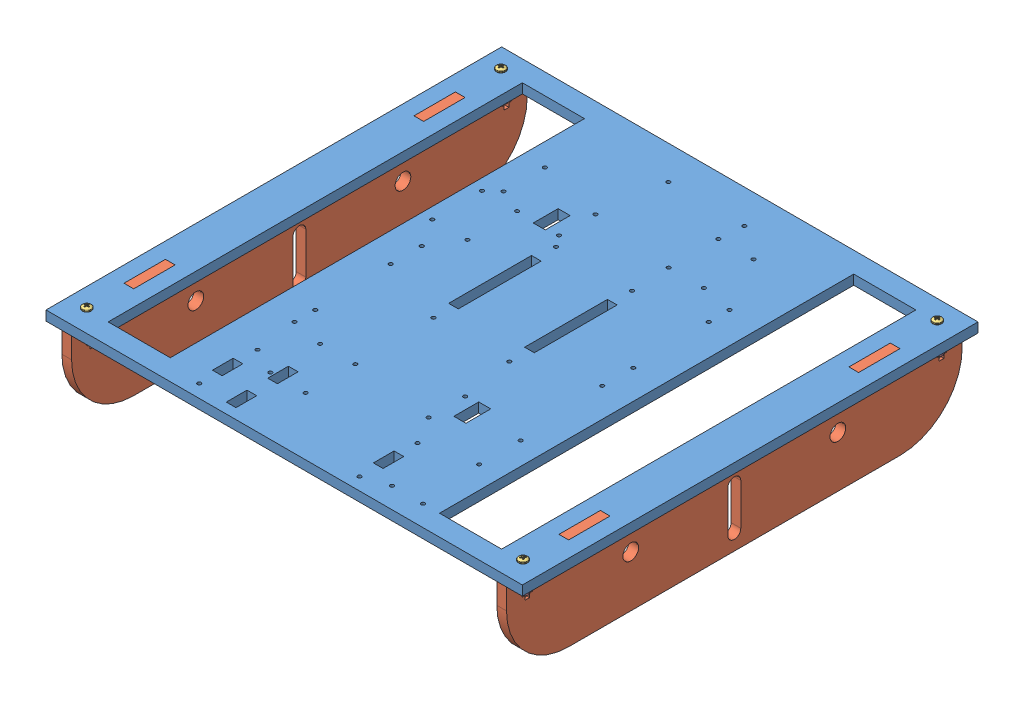
SolidWorks assembly Chassis_v1.0, configuration Default. Lengths in mm.
Overall size (292.1 59.18 279.4).
11 component instances, 4 part files, 28 mates.
Components (placement in the parent):
- Chassis_top-1: Chassis_top [Default] at (28.6473 8.8648 -23.2964) size (292.1 5.94 279.4)
- Chassis_Side-1: Chassis_Side [Default] at (164.9754 -16.5352 -23.2964) x (0 0 1) z (-1 0 0) size (279.4 56.74 5.94)
- Chassis_Side-2: Chassis_Side [Default] at (-107.6682 -16.5352 -23.2964) x (0 0 -1) z (1 0 0) size (279.4 56.74 5.94)
- 91772A113_18-8 SS PAN HEAD PHILLIPS MACHINE SCREW-1: 91772A113_18-8 SS PAN HEAD PHILLIPS MACHINE SCREW [91772A113] at (162.4037 -3.8352 103.7036) x (0.543796 0 -0.839218) z (0 1 0) size (5.56 5.56 21.36)
- 90480A005_LOW-STRENGTH STEEL HEX NUT-1: 90480A005_LOW-STRENGTH STEEL HEX NUT [90480A005] at (162.4037 -0.1046 103.7036) x (0.866025 0 0.5) z (-0.5 0 0.866025) size (6.35 2.87 7.33)
- 90480A005_LOW-STRENGTH STEEL HEX NUT-2: 90480A005_LOW-STRENGTH STEEL HEX NUT [90480A005] at (-105.1091 -0.1046 103.7036) x (0.866025 0 -0.5) z (0.5 0 0.866025) size (6.35 2.87 7.33)
- 91772A113_18-8 SS PAN HEAD PHILLIPS MACHINE SCREW-2: 91772A113_18-8 SS PAN HEAD PHILLIPS MACHINE SCREW [91772A113] at (-105.1091 -3.8352 103.7036) x (1 0 0) z (0 1 0) size (5.56 5.56 21.36)
- 91772A113_18-8 SS PAN HEAD PHILLIPS MACHINE SCREW-3: 91772A113_18-8 SS PAN HEAD PHILLIPS MACHINE SCREW [91772A113] at (-105.1091 -3.8352 -150.2964) x (1 0 0) z (0 1 0) size (5.56 5.56 21.36)
- 90480A005_LOW-STRENGTH STEEL HEX NUT-3: 90480A005_LOW-STRENGTH STEEL HEX NUT [90480A005] at (-105.1091 -0.1046 -150.2964) x (0.866025 0 -0.5) z (0.5 0 0.866025) size (6.35 2.87 7.33)
- 90480A005_LOW-STRENGTH STEEL HEX NUT-4: 90480A005_LOW-STRENGTH STEEL HEX NUT [90480A005] at (162.4037 -0.1046 -150.2964) x (0.866025 0 -0.5) z (0.5 0 0.866025) size (6.35 2.87 7.33)
- 91772A113_18-8 SS PAN HEAD PHILLIPS MACHINE SCREW-5: 91772A113_18-8 SS PAN HEAD PHILLIPS MACHINE SCREW [91772A113] at (162.4037 -3.8352 -150.2964) x (1 0 0) z (0 1 0) size (5.56 5.56 21.36)
Mates (geometry in assembly coordinates):
- Coincident3: coincident: plane of Chassis_top-1 through (164.9627 8.8648 52.9036) normal (0 0 1); plane of Chassis_Side-1 through (159.0318 14.8084 52.9036) normal (0 0 -1)
- Coincident4: coincident: plane of Chassis_top-1 through (164.9627 8.8648 -99.4964) normal (0 0 -1); plane of Chassis_Side-1 through (159.0318 14.8084 -99.4964) normal (0 0 1)
- Coincident10: coincident: plane of Chassis_top-1 through (-107.6682 8.8648 -99.4964) normal (0 0 -1); plane of Chassis_Side-2 through (-101.7246 14.8084 -99.4964) normal (0 0 1)
- Coincident11: coincident: plane of Chassis_top-1 through (-107.6682 8.8648 78.3036) normal (0 0 -1); plane of Chassis_Side-2 through (-101.7246 8.8648 78.3036) normal (0 0 1)
- Parallel3: parallel: line of Chassis_top-1 through (-107.6682 14.8084 -124.8964) axis (0 0 1); line of Chassis_Side-2 through (-107.6682 14.8084 -124.8964) axis (0 0 1)
- Coincident23: coincident: line of Chassis_top-1 through (-107.6682 14.8084 52.9036) axis (0 0 1); line of Chassis_Side-2 through (-107.6682 14.8084 52.9036) axis (0 0 1)
- Coincident25: coincident: line of Chassis_top-1 through (159.0318 14.8084 52.9036) axis (0 0 1); line of Chassis_Side-1 through (159.0318 14.8084 78.3036) axis (0 0 -1)
- Coincident29: coincident: plane of Chassis_Side-1 through (165.3818 1.086 106.8786) normal (0 0 -1); plane of 90480A005_LOW-STRENGTH STEEL HEX NUT-1 through (160.5706 1.086 106.8786) normal (0 0 1)
- Coincident30: coincident: plane of Chassis_Side-1 through (165.3818 -1.2952 100.5286) normal (0 0 1); plane of 90480A005_LOW-STRENGTH STEEL HEX NUT-1 through (164.2368 1.086 100.5286) normal (0 0 -1)
- Coincident31: coincident: plane of Chassis_Side-1 through (165.3818 -1.2952 106.8786) normal (0 1 0); plane of 90480A005_LOW-STRENGTH STEEL HEX NUT-1 through (160.5706 -1.2952 100.5286) normal (0 -1 0)
- Coincident32: coincident: plane of Chassis_Side-1 through (165.3818 -3.8352 105.1768) normal (0 1 0); plane of 91772A113_18-8 SS PAN HEAD PHILLIPS MACHINE SCREW-1 through (162.4037 -3.8352 103.7036) normal (0 -1 0)
- Coincident33: coincident: plane of Chassis_Side-2 through (-108.0746 1.086 106.8786) normal (0 0 -1); plane of 90480A005_LOW-STRENGTH STEEL HEX NUT-2 through (-106.9422 1.086 106.8786) normal (0 0 1)
- Coincident34: coincident: plane of Chassis_Side-2 through (-108.0746 -1.2952 102.2304) normal (0 1 0); plane of 90480A005_LOW-STRENGTH STEEL HEX NUT-2 through (-108.7753 -1.2952 103.7036) normal (0 -1 0)
- Coincident35: coincident: plane of Chassis_Side-2 through (-108.0746 -3.8352 105.1768) normal (0 1 0); circle of 91772A113_18-8 SS PAN HEAD PHILLIPS MACHINE SCREW-2
- Coincident36: coincident: plane of Chassis_Side-2 through (-108.0746 -1.2952 -147.1214) normal (0 0 -1); plane of 90480A005_LOW-STRENGTH STEEL HEX NUT-3 through (-106.9422 1.086 -147.1214) normal (0 0 1)
- Coincident37: coincident: plane of Chassis_Side-2 through (-108.0746 1.086 -151.7696) normal (0 -1 0); plane of 90480A005_LOW-STRENGTH STEEL HEX NUT-3 through (-108.7753 1.086 -150.2964) normal (0 1 0)
- Coincident38: coincident: plane of Chassis_Side-2 through (-108.0746 -3.8352 -151.7696) normal (0 1 0); plane of 91772A113_18-8 SS PAN HEAD PHILLIPS MACHINE SCREW-3 through (-105.1091 -3.8352 -150.2964) normal (0 -1 0)
- Coincident39: coincident: plane of Chassis_Side-1 through (165.3818 1.086 -153.4714) normal (0 0 1); plane of 90480A005_LOW-STRENGTH STEEL HEX NUT-4 through (164.2368 1.086 -153.4714) normal (0 0 -1)
- Coincident40: coincident: plane of Chassis_Side-1 through (165.3818 -1.2952 -153.4714) normal (0 1 0); plane of 90480A005_LOW-STRENGTH STEEL HEX NUT-4 through (158.7375 -1.2952 -150.2964) normal (0 -1 0)
- Coincident41: coincident: plane of Chassis_Side-1 through (165.3818 -3.8352 -151.7696) normal (0 1 0); plane of 91772A113_18-8 SS PAN HEAD PHILLIPS MACHINE SCREW-5 through (162.4037 -3.8352 -150.2964) normal (0 -1 0)
- Concentric1: concentric: circle of Chassis_top-1; circle of 91772A113_18-8 SS PAN HEAD PHILLIPS MACHINE SCREW-1
- Concentric2: concentric: circle of Chassis_top-1; circle of 90480A005_LOW-STRENGTH STEEL HEX NUT-1
- Concentric3: concentric: circle of Chassis_top-1; circle of 91772A113_18-8 SS PAN HEAD PHILLIPS MACHINE SCREW-2
- Concentric4: concentric: circle of 90480A005_LOW-STRENGTH STEEL HEX NUT-2; circle of 91772A113_18-8 SS PAN HEAD PHILLIPS MACHINE SCREW-2
- Concentric5: concentric: circle of Chassis_top-1; circle of 91772A113_18-8 SS PAN HEAD PHILLIPS MACHINE SCREW-3
- Concentric6: concentric: circle of 91772A113_18-8 SS PAN HEAD PHILLIPS MACHINE SCREW-3; circle of 90480A005_LOW-STRENGTH STEEL HEX NUT-3
- Concentric7: concentric: circle of Chassis_top-1; circle of 91772A113_18-8 SS PAN HEAD PHILLIPS MACHINE SCREW-5
- Concentric8: concentric: circle of 90480A005_LOW-STRENGTH STEEL HEX NUT-4; circle of 91772A113_18-8 SS PAN HEAD PHILLIPS MACHINE SCREW-5
